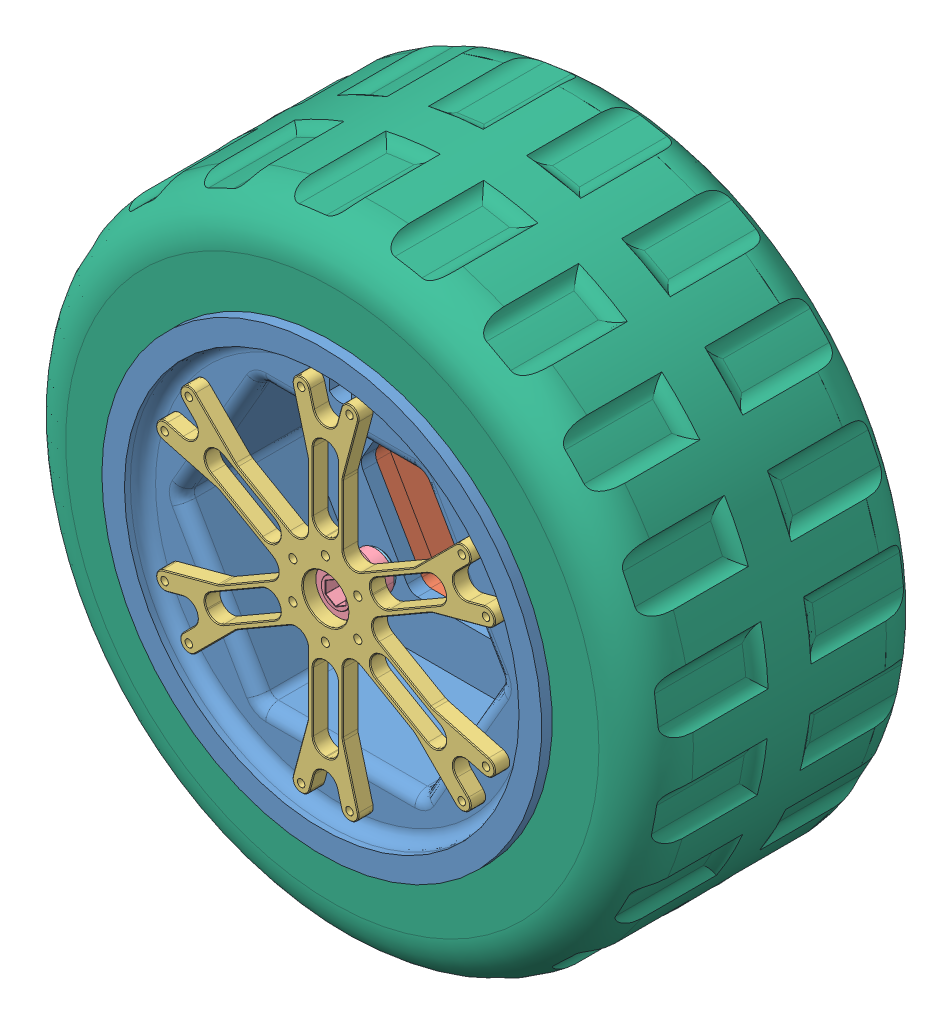
SolidWorks assembly UOR23-CNS-3-A-002_Wheel_assembly, configuration Default. Lengths in mm.
Overall size (401.56 401.56 196).
6 component instances, 6 part files, 15 mates.
Components (placement in the parent):
- UOR23-CNS-3-P-016-Wheel_Rim_Y_Hub_Connection-1: UOR23-CNS-3-P-016-Wheel_Rim_Y_Hub_Connection [Default] at origin size (279.4 279.4 98)
- UOR23-CNS-3-P-015-Wheel_Rim_Cantilever_Half-1: UOR23-CNS-3-P-015-Wheel_Rim_Cantilever_Half [Default] at (0 0 -18) x (-1 0 0) z (0 0 -1) size (279.4 279.4 98)
- UOR23-CNS-3-P-017-Y_Hub_Rim_Face-1: UOR23-CNS-3-P-017-Y_Hub_Rim_Face [Default] at (0 0 80.248) x (0.866025 -0.5 0) z (0.5 0.866025 0) size (229.11 9.53 215.28)
- UOR23-CNS-3-P-018-Hex_Hub_Adapter-1: UOR23-CNS-3-P-018-Hex_Hub_Adapter [Default] at (0 0 80.248) x (0 -1 0) z (1 0 0) size (55.37 25.4 51.33)
- UOR23-CNS-3-P-018-Hex_Shaft_to_Motor_Spacer-1: UOR23-CNS-3-P-018-Hex_Shaft_to_Motor_Spacer [Default] at (0 0 51.698) x (0.866025 0.5 0) z (0 0 1) size (22 22 3.15)
- UOR23-CNS-3-P-019-Tire-1: UOR23-CNS-3-P-019-Tire [Default] at (-81.6909 -213.0434 -180.71) size (401.56 401.56 182.6)
Mates (geometry in assembly coordinates):
- Coincident1: coincident anti-aligned: plane of UOR23-CNS-3-P-016-Wheel_Rim_Y_Hub_Connection-1 through (0 108.322 -9) normal (0 0 -1); plane of UOR23-CNS-3-P-015-Wheel_Rim_Cantilever_Half-1 through (0 108.322 -9) normal (0 0 1)
- Coincident2: coincident aligned: plane of UOR23-CNS-3-P-016-Wheel_Rim_Y_Hub_Connection-1 through (54.8483 95 65) normal (0 1 0); plane of UOR23-CNS-3-P-015-Wheel_Rim_Cantilever_Half-1 through (54.8483 95 -83) normal (0 1 0)
- Coincident3: coincident aligned: plane of UOR23-CNS-3-P-016-Wheel_Rim_Y_Hub_Connection-1 through (109.6966 0 65) normal (0.866025 0.5 0); plane of UOR23-CNS-3-P-015-Wheel_Rim_Cantilever_Half-1 through (54.8483 95 -83) normal (0.866025 0.5 0)
- Coincident4: coincident anti-aligned: plane of UOR23-CNS-3-P-016-Wheel_Rim_Y_Hub_Connection-1 through (0 0 77.2) normal (0 0 1); plane of UOR23-CNS-3-P-017-Y_Hub_Rim_Face-1 through (0 0 77.2) normal (0 0 -1)
- Concentric1: concentric aligned: cylinder of UOR23-CNS-3-P-016-Wheel_Rim_Y_Hub_Connection-1 through (15.377 109.0054 83.9175) axis (0 0 -1) radius 2.375; cylinder of UOR23-CNS-3-P-017-Y_Hub_Rim_Face-1 through (15.377 109.0054 194.6615) axis (0 0 -1) radius 2.375
- Concentric2: concentric aligned: cylinder of UOR23-CNS-3-P-016-Wheel_Rim_Y_Hub_Connection-1 through (-15.377 109.0054 83.9175) axis (0 0 -1) radius 2.375; cylinder of UOR23-CNS-3-P-017-Y_Hub_Rim_Face-1 through (-15.377 109.0054 194.6615) axis (0 0 -1) radius 2.375
- Coincident5: coincident anti-aligned: plane of UOR23-CNS-3-P-017-Y_Hub_Rim_Face-1 through (0 0 77.2) normal (0 0 -1); plane of UOR23-CNS-3-P-018-Hex_Hub_Adapter-1 through (0 38.1 77.2) normal (0 0 1)
- Concentric3: concentric aligned: cylinder of UOR23-CNS-3-P-017-Y_Hub_Rim_Face-1 through (0 23.8125 94.0529) axis (0 0 -1) radius 2.5908; cylinder of UOR23-CNS-3-P-018-Hex_Hub_Adapter-1 through (0 23.8125 80.248) axis (0 0 -1) radius 2.5908
- Concentric4: concentric aligned: cylinder of UOR23-CNS-3-P-017-Y_Hub_Rim_Face-1 through (-20.6222 11.9062 94.0529) axis (0 0 -1) radius 2.5908; cylinder of UOR23-CNS-3-P-018-Hex_Hub_Adapter-1 through (-20.6222 11.9062 80.248) axis (0 0 -1) radius 2.5908
- Concentric5: concentric anti-aligned: cylinder of UOR23-CNS-3-P-018-Hex_Hub_Adapter-1 through (0 0 54.848) axis (0 0 1) radius 12.1666; cylinder of UOR23-CNS-3-P-018-Hex_Shaft_to_Motor_Spacer-1 through (0 0 54.848) axis (0 0 -1) radius 11
- Coincident6: coincident anti-aligned: plane of UOR23-CNS-3-P-018-Hex_Hub_Adapter-1 through (0 0 54.848) normal (0 0 -1); plane of UOR23-CNS-3-P-018-Hex_Shaft_to_Motor_Spacer-1 through (0 0 54.848) normal (0 0 1)
- Parallel1: parallel aligned: plane of UOR23-CNS-3-P-018-Hex_Hub_Adapter-1 through (-6.3627 3.6735 80.248) normal (0.5 -0.866025 0); plane of UOR23-CNS-3-P-018-Hex_Shaft_to_Motor_Spacer-1 through (0 8.3716 54.848) normal (0.5 -0.866025 0)
- Coincident8: coincident: plane of UOR23-CNS-3-P-016-Wheel_Rim_Y_Hub_Connection-1 through (0 0 65) normal (0 0 -1); plane of UOR23-CNS-3-P-019-Tire-1 through (0 0 65) normal (0 0 1)
- Concentric6: concentric: cylinder of UOR23-CNS-3-P-015-Wheel_Rim_Cantilever_Half-1 through (0 0 -107) axis (0 0 1) radius 139.7; cylinder of UOR23-CNS-3-P-019-Tire-1 through (0 0 -664.2601) axis (0 0 1) radius 199.39
- Concentric7: concentric anti-aligned: circle of UOR23-CNS-3-P-016-Wheel_Rim_Y_Hub_Connection-1; cylinder of UOR23-CNS-3-P-019-Tire-1 through (0 108.322 460.1313) axis (0 0 -1) radius 13
